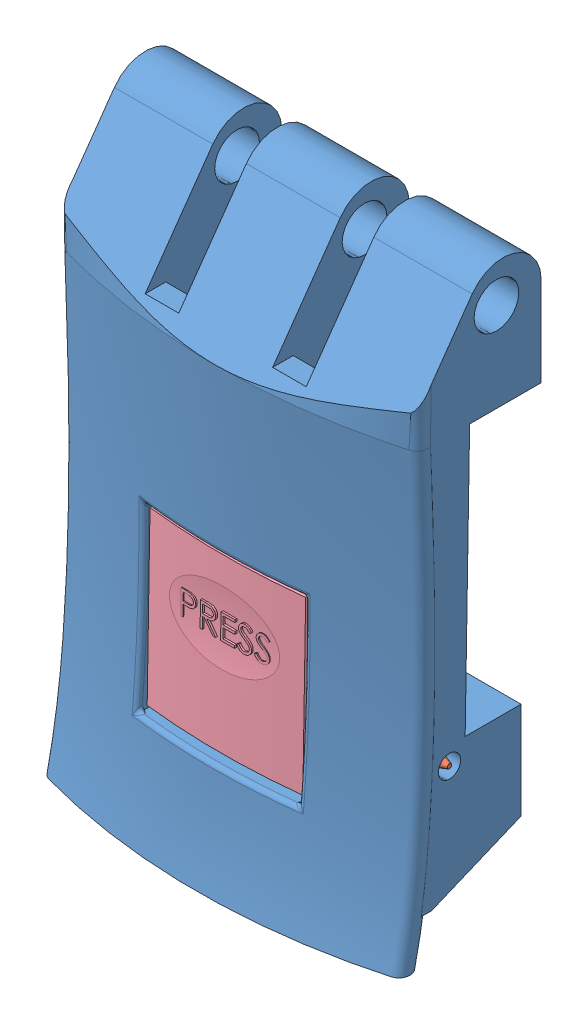
SolidWorks assembly side latch, configuration Default. Lengths in mm.
Overall size (51.15 81.59 23.77).
4 component instances, 4 part files, 9 mates.
Components (placement in the parent):
- side latch main-1: side latch main [Default] at origin size (51.15 81.59 23.77)
- side latch button pin-1: side latch button pin [Default] at (0 -40.64 -6.35) size (50.8 3.17 3.17)
- side latch button spring-1: side latch button spring [Default] at (3.1752 -40.64 -6.35) x (1 0 0) z (0 -0.978148 0.207912) size (7.25 8.76 24.29)
- side latch button-1: side latch button [Default] at (0 -36.0898 -0.075) x (1 0 0) z (0 -0.999861 0.016664) size (22.1 17.14 31.12)
Mates (geometry in assembly coordinates):
- Coincident1: coincident: axis of side latch main-1 through (11.43 -40.64 -6.35) axis (1 0 0); axis of side latch button pin-1 through (21.59 -40.64 -6.35) axis (-1 0 0)
- Coincident2: coincident: plane of side latch main-1 through (25.4 0 -3.6543) normal (1 0 0); plane of side latch button pin-1 through (25.4 -40.64 -6.35) normal (1 0 0)
- Parallel1: parallel: plane of side latch main-1 through (0 0 0) normal (0 0 1); plane of side latch button pin-1 through (0 -40.64 -6.35) normal (0 0 1)
- Tangent1: tangent: cylinder of side latch button pin-1 through (25.4 -40.64 -6.35) axis (-1 0 0) radius 1.5875; face of side latch button spring-1
- Coincident3: coincident: plane of side latch button pin-1 through (0 -40.64 -6.35) normal (1 0 0); plane of side latch button spring-1
- Parallel2: parallel: plane of side latch main-1 through (3.81 -52.6586 -0.1496) normal (0 0.978148 -0.207912); plane of side latch button spring-1 through (3.1752 -52.64 -1.7219) normal (0 -0.978148 0.207912)
- Coincident12: coincident: axis of side latch button pin-1 through (21.59 -40.64 -6.35) axis (-1 0 0); axis of side latch button-1 through (4.0005 -40.64 -6.35) axis (1 0 0)
- Coincident13: coincident: plane of side latch button pin-1 through (0 -40.64 -6.35) normal (1 0 0); plane of side latch button-1
- Parallel5: parallel: plane of side latch main-1 through (11.43 -20.0844 -2.5218) normal (0 -0.016664 -0.999861); plane of side latch button-1 through (45.1562 -48.1955 -2.4135) normal (0 0.016664 0.999861)
